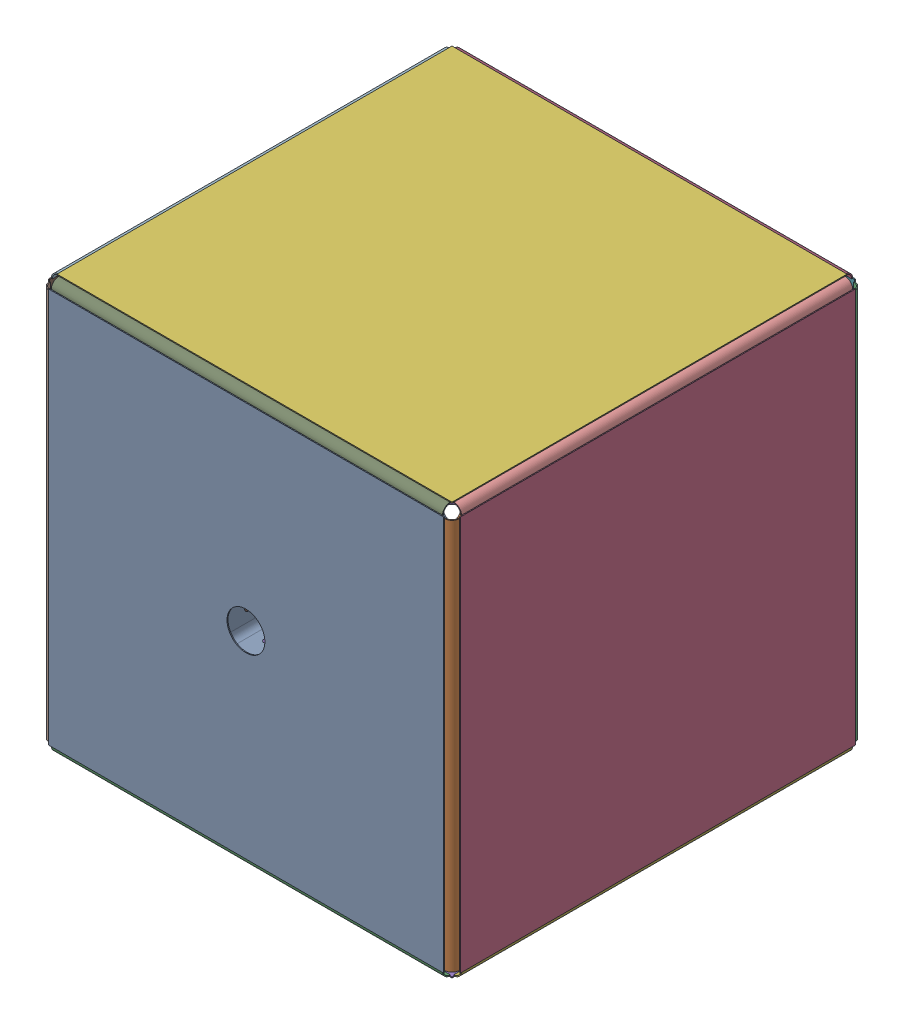
SolidWorks assembly inner_layer, configuration Default. Lengths in mm.
Overall size (653 653 653).
18 component instances, 3 part files, 13 mates.
Components (placement in the parent):
- inner_flat_front-5: inner_flat_front [Default] at (0 0 326.5) x (-1 0 0) z (0 0 -1) size (626 626 3)
- inner_bracket-44: inner_bracket [Default] at (323.5 0 268.5) x (1 0 0) z (0 0 -1) size (56.5 620 56.5)
- inner_bracket-45: inner_bracket [Default] at (0 -323.5 268.5) x (0 -1 0) z (0 0 -1) size (56.5 620 56.5)
- inner_flat-22: inner_flat [Default] at (325 0 0) x (0 0 -1) z (1 0 0) size (626 626 3)
- inner_flat-23: inner_flat [Default] at (0 -325 0) x (1 0 0) z (0 -1 0) size (626 626 3)
- inner_bracket-48: inner_bracket [Default] at (268.5 -323.5 0) x (0 -1 0) z (-1 0 0) size (56.5 620 56.5)
- inner_flat-26: inner_flat [Default] at (0 0 -325) x (-1 0 0) z (0 0 -1) size (626 626 3)
- inner_bracket-46: inner_bracket [Default] at (-323.5 0 268.5) x (-1 0 0) z (0 0 -1) size (56.5 620 56.5)
- inner_bracket-47: inner_bracket [Default] at (0 323.5 268.5) x (0 1 0) z (0 0 -1) size (56.5 620 56.5)
- inner_bracket-49: inner_bracket [Default] at (268.5 323.5 0) x (0 1 0) z (-1 0 0) size (56.5 620 56.5)
- inner_flat-24: inner_flat [Default] at (-325 0 0) x (0 0 1) z (-1 0 0) size (626 626 3)
- inner_bracket-50: inner_bracket [Default] at (-268.5 323.5 0) x (0 1 0) z (1 0 0) size (56.5 620 56.5)
- inner_bracket-51: inner_bracket [Default] at (-268.5 -323.5 0) x (0 -1 0) z (1 0 0) size (56.5 620 56.5)
- inner_bracket-52: inner_bracket [Default] at (0 -323.5 -268.5) x (0 -1 0) z (0 0 1) size (56.5 620 56.5)
- inner_bracket-53: inner_bracket [Default] at (323.5 0 -268.5) size (56.5 620 56.5)
- inner_bracket-54: inner_bracket [Default] at (0 323.5 -268.5) x (0 1 0) z (0 0 1) size (56.5 620 56.5)
- inner_bracket-55: inner_bracket [Default] at (-323.5 0 -268.5) x (-1 0 0) z (0 0 1) size (56.5 620 56.5)
- inner_flat-25: inner_flat [Default] at (0 325 0) x (-1 0 0) z (0 1 0) size (626 626 3)
Mates (geometry in assembly coordinates):
- Concentric18: concentric aligned: circle of inner_flat_front-5; circle of inner_bracket-44
- Distance16: distance = 0 mm anti-aligned: plane of inner_bracket-44 through (325 0 325) normal (0 0 1); plane of inner_flat_front-5 through (0 0 325) normal (0 0 -1)
- Concentric19: concentric aligned: circle of inner_flat_front-5; circle of inner_bracket-45
- Distance17: distance = 0 mm anti-aligned: plane of inner_flat_front-5 through (0 0 325) normal (0 0 -1); plane of inner_bracket-45 through (0 -325 325) normal (0 0 1)
- Distance18: distance = 0 mm anti-aligned: plane of inner_flat-23 through (0 -325 0) normal (0 1 0); plane of inner_bracket-45 through (0 -325 268.5) normal (0 -1 0)
- Concentric20: concentric anti-aligned: circle of inner_bracket-45; circle of inner_flat-23
- Distance19: distance = 0 mm anti-aligned: plane of inner_flat-22 through (325 0 0) normal (-1 0 0); plane of inner_bracket-44 through (325 0 268.5) normal (1 0 0)
- Concentric21: concentric anti-aligned: circle of inner_bracket-44; circle of inner_flat-22
- Coincident46: coincident anti-aligned: plane of inner_flat-23 through (0 -325 0) normal (0 1 0); plane of inner_bracket-48 through (268.5 -325 0) normal (0 -1 0)
- Coincident47: coincident anti-aligned: plane of inner_flat-22 through (325 0 0) normal (-1 0 0); plane of inner_bracket-48 through (325 -325 0) normal (1 0 0)
- Concentric22: concentric anti-aligned: circle of inner_flat-23; circle of inner_bracket-48
- Concentric23: concentric aligned: circle of inner_bracket-54; circle of inner_flat-26
- Coincident50: coincident anti-aligned: plane of inner_bracket-54 through (0 325 -325) normal (0 0 -1); plane of inner_flat-26 through (0 0 -325) normal (0 0 1)
